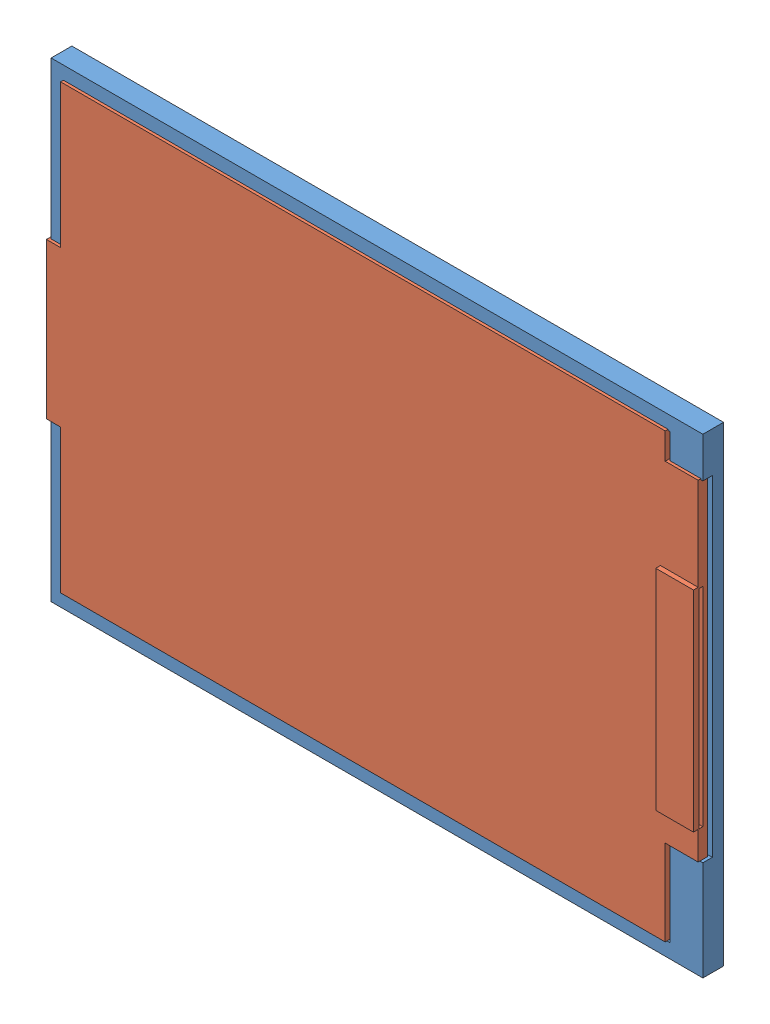
SolidWorks assembly YFY24NPQV824, configuration Défaut. Lengths in mm.
Overall size (69.4 50 3).
2 component instances, 2 part files, 0 mates.
Components (placement in the parent):
- YFY24NPQV824-1: YFY24NPQV824 [Défaut] at (-2.9033 -0.9201 68.1) size (69.2 50 2.2)
- YFY24NPQV824display-1: YFY24NPQV824display [Défaut] at (-3.1059 -0.8104 69.5982) size (69.2 47 1.5)
